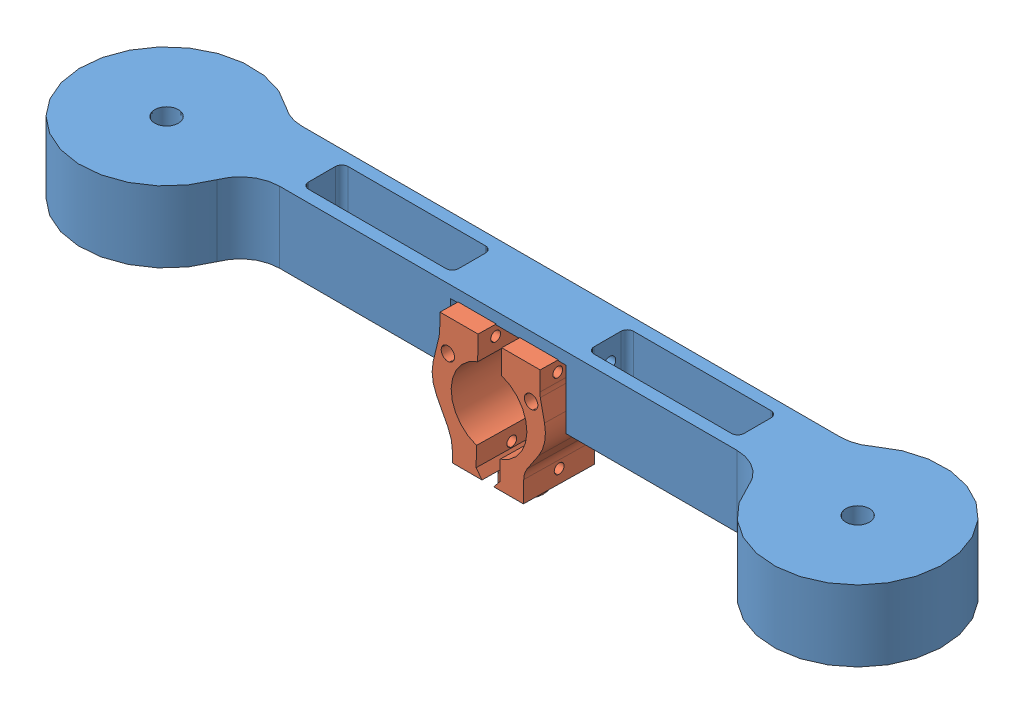
SolidWorks assembly Bridge Assembly, configuration Default. Lengths in mm.
Overall size (218.18 38.49 43.18).
2 component instances, 2 part files, 2 mates.
Components (placement in the parent):
- Bridge1-1: Bridge1 [Default] at (-91.0313 10.4459 12.9885) size (218.18 18 43.18)
- MagnetHolderTrimmedC-1: MagnetHolderTrimmedC [Default] at (-32.9013 -9.9019 3.7025) x (1 0 0) z (0 0.016713 0.99986) size (29.41 36.25 18)
Mates (geometry in assembly coordinates):
- Perpendicular1: perpendicular: line of Bridge1-1; line of MagnetHolderTrimmedC-1
- Coincident2: coincident aligned: line of Bridge1-1; line of MagnetHolderTrimmedC-1
